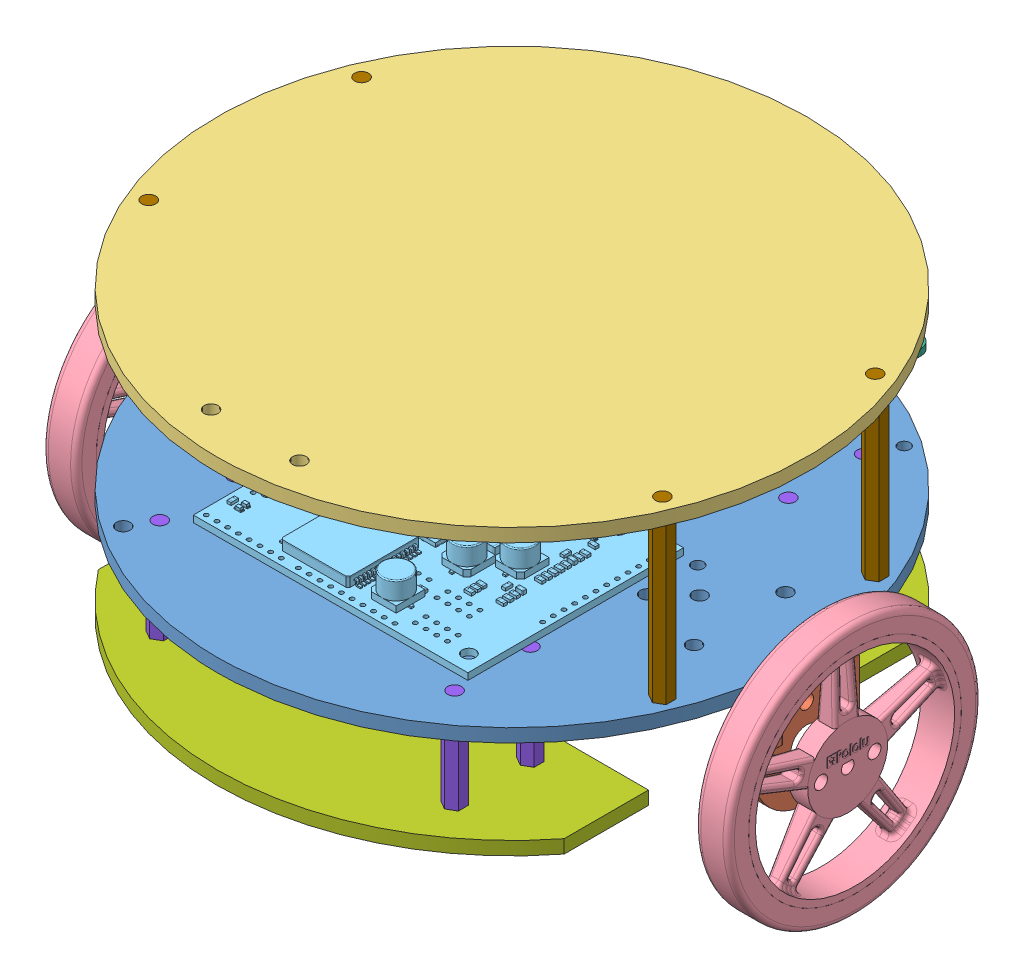
SolidWorks assembly Fleet v0.2, configuration Default. Lengths in mm.
Overall size (162.9 88.85 140).
25 component instances, 11 part files, 57 mates.
Components (placement in the parent):
- Main Plate 1-1: Main Plate 1 [Default] at (53.2584 52.989 119.4914) size (140 3.17 140)
- pololu-25d-mm-metal-gearmotor-bracket-1: pololu-25d-mm-metal-gearmotor-bracket [Default] at (108.7084 39.489 120.4914) x (0 0 1) z (1 0 0) size (25 27 52)
- pololu-25d-mm-metal-gearmotor-bracket-2: pololu-25d-mm-metal-gearmotor-bracket [Default] at (-2.1916 39.489 118.4914) x (0 0 -1) z (-1 0 0) size (25 27 52)
- 25d-metal-gearmotor-20.4-encoder-1: 25d-metal-gearmotor-20.4-encoder [Default] at (3.6834 38.489 88.6164) x (0 0 1) z (-1 0 0) (suppressed, hidden)
- 25d-metal-gearmotor-20.4-encoder-2: 25d-metal-gearmotor-20.4-encoder [Default] at (102.8334 38.489 150.3664) x (0 0 -1) z (1 0 0) (suppressed, hidden)
- Main Plate 2-2: Main Plate 2 [Default] at (53.2584 94.164 119.4914) size (140 3.17 140)
- pololu-wheel-60x8mm-black-1: pololu-wheel-60x8mm-black [Default] at (130.7084 38.489 119.4914) size (11 60 60)
- pololu-wheel-60x8mm-black-2: pololu-wheel-60x8mm-black [Default] at (-24.1916 38.489 119.4914) x (-1 0 0) z (0 0 -1) size (11 60 60)
- ArduinoMega-1: ArduinoMega [Default] at (51.7791 57.815 149.4373) x (-0.999997 0 0.002348) z (0 -1 0) (suppressed, hidden)
- pololu-dual-vnh5019-motor-driver-shield-1: pololu-dual-vnh5019-motor-driver-shield [Default] at (97.8699 66.3748 123.3829) x (-0.999997 0 0.002348) z (0 1 0) size (65.02 51.31 7.68)
- Rpi3Bplus-1: Rpi3Bplus [Default] at (94.8584 76.1894 60.9914) x (-1 0 0) z (0 0 -1) size (87.03 17.52 58.47)
- SubPlate 1-1: SubPlate 1 [Default] at (53.2584 29.814 119.4914) x (-1 0 0) z (0 0 -1) size (110.61 3.17 47.09)
- SubPlate 1-2: SubPlate 1 [Default] at (53.2584 29.814 119.4914) size (110.61 3.17 47.09)
- 20mm standoff-1: 20mm standoff [Default] at (88.2584 32.989 168.1132) size (4.15 26.35 4.79)
- 20mm standoff-2: 20mm standoff [Default] at (18.2584 32.989 168.1132) size (4.15 26.35 4.79)
- 20mm standoff-3: 20mm standoff [Default] at (18.2584 32.989 150.1132) size (4.15 26.35 4.79)
- 20mm standoff-4: 20mm standoff [Default] at (88.2584 32.989 150.1132) size (4.15 26.35 4.79)
- 20mm standoff-5: 20mm standoff [Default] at (18.2584 32.989 70.8696) size (4.15 26.35 4.79)
- 20mm standoff-6: 20mm standoff [Default] at (88.2584 32.989 88.8696) size (4.15 26.35 4.79)
- 20mm standoff-7: 20mm standoff [Default] at (88.2584 32.989 70.8696) size (4.15 26.35 4.79)
- 20mm standoff-8: 20mm standoff [Default] at (18.2584 32.989 88.8696) size (4.15 26.35 4.79)
- 38mm standoff-1: 38mm standoff [Default] at (114.2344 56.164 94.2343) size (4.15 44.35 4.79)
- 38mm standoff-2: 38mm standoff [Default] at (114.2344 56.164 144.7485) size (4.15 44.35 4.79)
- 38mm standoff-3: 38mm standoff [Default] at (-7.7177 56.164 94.2343) size (4.15 44.35 4.79)
- 38mm standoff-4: 38mm standoff [Default] at (-7.7177 56.164 144.7485) size (4.15 44.35 4.79)
Mates (geometry in assembly coordinates):
- Coincident1: coincident anti-aligned: plane of Main Plate 1-1 through (53.2584 52.989 119.4914) normal (0 -1 0); plane of pololu-25d-mm-metal-gearmotor-bracket-1 through (121.2084 52.989 131.9914) normal (0 1 0)
- Concentric3: concentric anti-aligned: circle of Main Plate 1-1; circle of pololu-25d-mm-metal-gearmotor-bracket-1
- Coincident2: coincident anti-aligned: plane of Main Plate 1-1 through (53.2584 52.989 119.4914) normal (0 -1 0); plane of pololu-25d-mm-metal-gearmotor-bracket-2 through (-14.6916 52.989 106.9914) normal (0 1 0)
- Concentric4: concentric aligned: circle of Main Plate 1-1; circle of pololu-25d-mm-metal-gearmotor-bracket-2
- Coincident3: coincident anti-aligned: plane of pololu-25d-mm-metal-gearmotor-bracket-1 through (121.2084 50.989 131.9914) normal (-1 0 0); plane of 25d-metal-gearmotor-20.4-encoder-2 through (121.2084 38.489 119.4914) normal (1 0 0)
- Concentric5: concentric anti-aligned: circle of pololu-25d-mm-metal-gearmotor-bracket-1; circle of 25d-metal-gearmotor-20.4-encoder-2
- Coincident4: coincident anti-aligned: plane of pololu-25d-mm-metal-gearmotor-bracket-2 through (-14.6916 50.989 106.9914) normal (1 0 0); plane of 25d-metal-gearmotor-20.4-encoder-1 through (-14.6916 38.489 119.4914) normal (-1 0 0)
- Concentric6: concentric anti-aligned: circle of pololu-25d-mm-metal-gearmotor-bracket-2; circle of 25d-metal-gearmotor-20.4-encoder-1
- Concentric7: concentric anti-aligned: circle of pololu-25d-mm-metal-gearmotor-bracket-2; circle of 25d-metal-gearmotor-20.4-encoder-1
- Distance2: distance = 38 mm anti-aligned: plane of Main Plate 2-2 through (53.2584 94.164 119.4914) normal (0 -1 0); plane of Main Plate 1-1 through (53.2584 56.164 119.4914) normal (0 1 0)
- Concentric8: concentric aligned: circle of Main Plate 1-1; circle of Main Plate 2-2
- Concentric13: concentric anti-aligned: circle of pololu-25d-mm-metal-gearmotor-bracket-1; cylinder of 25d-metal-gearmotor-20.4-encoder-2 through (118.3584 46.989 119.4914) axis (1 0 0) radius 1.25
- Concentric18: concentric aligned: circle of 25d-metal-gearmotor-20.4-encoder-1; circle of pololu-wheel-60x8mm-black-2
- Parallel3: parallel anti-aligned: plane of 25d-metal-gearmotor-20.4-encoder-1 through (-19.1916 39.989 119.4914) normal (0 1 0); plane of pololu-wheel-60x8mm-black-2 through (-28.1916 39.489 120.6094) normal (0 -1 0)
- Concentric19: concentric aligned: circle of 25d-metal-gearmotor-20.4-encoder-2; circle of pololu-wheel-60x8mm-black-1
- Coincident11: coincident anti-aligned: plane of 25d-metal-gearmotor-20.4-encoder-2 through (123.7084 38.489 119.4914) normal (1 0 0); plane of pololu-wheel-60x8mm-black-1 through (123.7084 38.489 119.4914) normal (-1 0 0)
- Coincident12: coincident anti-aligned: plane of 25d-metal-gearmotor-20.4-encoder-1 through (-17.1916 38.489 119.4914) normal (-1 0 0); plane of pololu-wheel-60x8mm-black-2 through (-17.1916 38.489 119.4914) normal (1 0 0)
- Concentric20: concentric anti-aligned: circle of Main Plate 1-1; cylinder of pololu-25d-mm-metal-gearmotor-bracket-2 through (-0.8166 52.989 108.6414) axis (0 -1 0) radius 1.65
- Concentric21: concentric anti-aligned: circle of Main Plate 1-1; cylinder of pololu-25d-mm-metal-gearmotor-bracket-1 through (107.3334 52.989 108.6414) axis (0 -1 0) radius 1.65
- Coincident13: coincident anti-aligned: plane of Main Plate 1-1 through (53.2584 56.164 119.4914) normal (0 1 0); plane of ArduinoMega-1 through (1.042 56.164 176.2646) normal (0 -1 0)
- Coincident14: coincident anti-aligned: plane of ArduinoMega-1 through (48.6637 66.3748 174.8066) normal (0 1 0); plane of pololu-dual-vnh5019-motor-driver-shield-1 through (97.8699 66.3748 123.3829) normal (0 -1 0)
- Coincident15: coincident aligned: plane of ArduinoMega-1 through (71.6506 66.3748 174.7526) normal (0.002348 0 0.999997); plane of pololu-dual-vnh5019-motor-driver-shield-1 through (32.9665 67.9496 174.8434) normal (0.002348 0 0.999997)
- Coincident17: coincident aligned: plane of ArduinoMega-1 through (32.9608 66.3748 172.394) normal (-0.999997 0 0.002348); plane of pololu-dual-vnh5019-motor-driver-shield-1 through (32.8461 67.9496 123.5355) normal (-0.999997 0 0.002348)
- Concentric24: concentric aligned: circle of Main Plate 1-1; circle of ArduinoMega-1
- Concentric28: concentric aligned: circle of Main Plate 1-1; circle of Rpi3Bplus-1
- Concentric29: concentric anti-aligned: cylinder of Main Plate 1-1 through (91.3584 56.164 64.4914) axis (0 -1 0) radius 1.4; circle of Rpi3Bplus-1
- Distance3: distance = 20 mm anti-aligned: plane of SubPlate 1-2 through (53.2584 32.989 119.4914) normal (0 1 0); plane of Main Plate 1-1 through (53.2584 52.989 119.4914) normal (0 -1 0)
- Concentric31: concentric aligned: cylinder of Main Plate 1-1 through (18.2584 56.164 70.8696) axis (0 -1 0) radius 1.65; cylinder of SubPlate 1-2 through (18.2584 32.989 70.8696) axis (0 -1 0) radius 1.65
- Coincident28: coincident anti-aligned: cylinder of Main Plate 1-1 through (88.2584 56.164 88.8696) axis (0 -1 0) radius 1.65; circle of SubPlate 1-2
- Distance4: distance = 20 mm anti-aligned: plane of SubPlate 1-1 through (53.2584 32.989 119.4914) normal (0 1 0); plane of Main Plate 1-1 through (53.2584 52.989 119.4914) normal (0 -1 0)
- Concentric32: concentric aligned: cylinder of Main Plate 1-1 through (88.2584 56.164 168.1132) axis (0 -1 0) radius 1.65; cylinder of SubPlate 1-1 through (88.2584 32.989 168.1132) axis (0 -1 0) radius 1.65
- Concentric33: concentric aligned: circle of Main Plate 1-1; circle of SubPlate 1-1
- Coincident31: coincident anti-aligned: circle of SubPlate 1-1; cylinder of 20mm standoff-1 through (88.2584 52.989 168.1132) axis (0 -1 0) radius 1.65
- Coincident32: coincident anti-aligned: plane of Main Plate 1-1 through (53.2584 52.989 119.4914) normal (0 -1 0); plane of 20mm standoff-1 through (88.2584 52.989 168.1132) normal (0 1 0)
- Concentric34: concentric anti-aligned: cylinder of SubPlate 1-1 through (18.2584 32.989 168.1132) axis (0 -1 0) radius 1.65; cylinder of 20mm standoff-2 through (18.2584 29.814 168.1132) axis (0 1 0) radius 1.65
- Coincident33: coincident anti-aligned: plane of SubPlate 1-1 through (53.2584 32.989 119.4914) normal (0 1 0); plane of 20mm standoff-2 through (18.2584 32.989 168.1132) normal (0 -1 0)
- Concentric35: concentric anti-aligned: cylinder of SubPlate 1-1 through (88.2584 32.989 150.1132) axis (0 -1 0) radius 1.65; cylinder of 20mm standoff-4 through (88.2584 29.814 150.1132) axis (0 1 0) radius 1.65
- Coincident34: coincident anti-aligned: plane of SubPlate 1-1 through (53.2584 32.989 119.4914) normal (0 1 0); plane of 20mm standoff-4 through (88.2584 32.989 150.1132) normal (0 -1 0)
- Concentric36: concentric anti-aligned: cylinder of SubPlate 1-1 through (18.2584 32.989 150.1132) axis (0 -1 0) radius 1.65; cylinder of 20mm standoff-3 through (18.2584 29.814 150.1132) axis (0 1 0) radius 1.65
- Coincident35: coincident anti-aligned: plane of SubPlate 1-1 through (53.2584 32.989 119.4914) normal (0 1 0); plane of 20mm standoff-3 through (18.2584 32.989 150.1132) normal (0 -1 0)
- Concentric37: concentric anti-aligned: cylinder of SubPlate 1-2 through (88.2584 32.989 70.8696) axis (0 -1 0) radius 1.65; cylinder of 20mm standoff-7 through (88.2584 29.814 70.8696) axis (0 1 0) radius 1.65
- Coincident36: coincident anti-aligned: plane of SubPlate 1-2 through (53.2584 32.989 119.4914) normal (0 1 0); plane of 20mm standoff-7 through (88.2584 32.989 70.8696) normal (0 -1 0)
- Concentric38: concentric anti-aligned: cylinder of SubPlate 1-2 through (18.2584 32.989 70.8696) axis (0 -1 0) radius 1.65; cylinder of 20mm standoff-5 through (18.2584 29.814 70.8696) axis (0 1 0) radius 1.65
- Coincident37: coincident anti-aligned: plane of SubPlate 1-2 through (53.2584 32.989 119.4914) normal (0 1 0); plane of 20mm standoff-5 through (18.2584 32.989 70.8696) normal (0 -1 0)
- Concentric39: concentric anti-aligned: cylinder of SubPlate 1-2 through (88.2584 32.989 88.8696) axis (0 -1 0) radius 1.65; cylinder of 20mm standoff-6 through (88.2584 29.814 88.8696) axis (0 1 0) radius 1.65
- Coincident38: coincident anti-aligned: plane of SubPlate 1-2 through (53.2584 32.989 119.4914) normal (0 1 0); plane of 20mm standoff-6 through (88.2584 32.989 88.8696) normal (0 -1 0)
- Concentric40: concentric anti-aligned: cylinder of SubPlate 1-2 through (18.2584 32.989 88.8696) axis (0 -1 0) radius 1.65; cylinder of 20mm standoff-8 through (18.2584 29.814 88.8696) axis (0 1 0) radius 1.65
- Coincident39: coincident anti-aligned: plane of SubPlate 1-2 through (53.2584 32.989 119.4914) normal (0 1 0); plane of 20mm standoff-8 through (18.2584 32.989 88.8696) normal (0 -1 0)
- Concentric41: concentric anti-aligned: cylinder of Main Plate 1-1 through (114.2344 56.164 94.2343) axis (0 -1 0) radius 1.65; cylinder of 38mm standoff-1 through (114.2344 52.989 94.2343) axis (0 1 0) radius 1.65
- Coincident40: coincident anti-aligned: plane of Main Plate 1-1 through (53.2584 56.164 119.4914) normal (0 1 0); plane of 38mm standoff-1 through (114.2344 56.164 94.2343) normal (0 -1 0)
- Concentric42: concentric anti-aligned: cylinder of Main Plate 1-1 through (114.2344 56.164 144.7485) axis (0 -1 0) radius 1.65; cylinder of 38mm standoff-2 through (114.2344 52.989 144.7485) axis (0 1 0) radius 1.65
- Coincident41: coincident anti-aligned: plane of Main Plate 1-1 through (53.2584 56.164 119.4914) normal (0 1 0); plane of 38mm standoff-2 through (114.2344 56.164 144.7485) normal (0 -1 0)
- Concentric43: concentric anti-aligned: cylinder of Main Plate 1-1 through (-7.7177 56.164 94.2343) axis (0 -1 0) radius 1.65; cylinder of 38mm standoff-3 through (-7.7177 52.989 94.2343) axis (0 1 0) radius 1.65
- Coincident42: coincident anti-aligned: plane of Main Plate 1-1 through (53.2584 56.164 119.4914) normal (0 1 0); plane of 38mm standoff-3 through (-7.7177 56.164 94.2343) normal (0 -1 0)
- Concentric44: concentric anti-aligned: cylinder of Main Plate 1-1 through (-7.7177 56.164 144.7485) axis (0 -1 0) radius 1.65; cylinder of 38mm standoff-4 through (-7.7177 52.989 144.7485) axis (0 1 0) radius 1.65
- Coincident43: coincident anti-aligned: plane of Main Plate 1-1 through (53.2584 56.164 119.4914) normal (0 1 0); plane of 38mm standoff-4 through (-7.7177 56.164 144.7485) normal (0 -1 0)
- Distance5: distance = 20 mm anti-aligned: plane of Rpi3Bplus-1 through (12.8584 76.164 63.9914) normal (0 -1 0); plane of Main Plate 1-1 through (53.2584 56.164 119.4914) normal (0 1 0)
